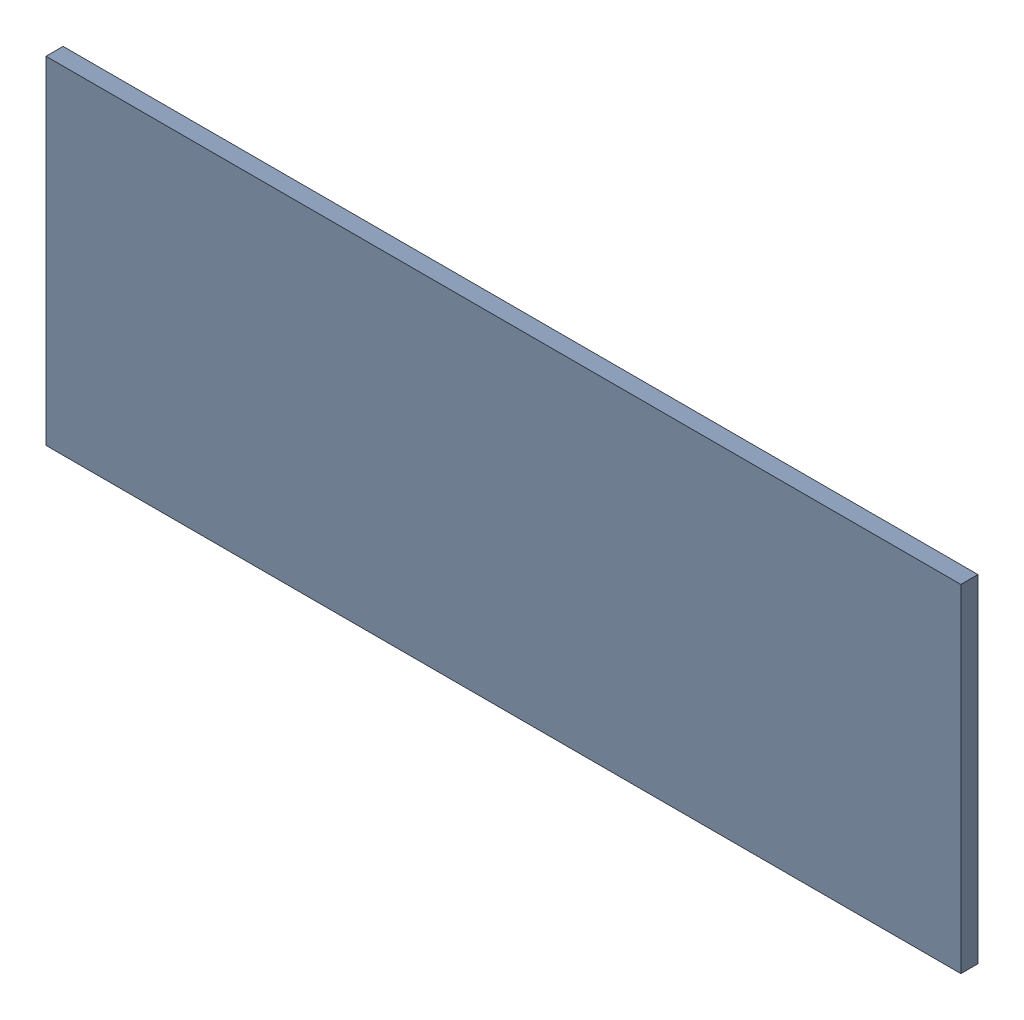
SolidWorks assembly Pad RAK4600-7(14.5mm,20mm) on Top Layer, configuration Predeterminado. Lengths in mm.
Overall size (1.9 0.7 0.04).
2 component instances, 1 part files, 0 mates.
Components (placement in the parent):
- Pad RAK4600-7(14.5mm,20mm) on Top Layer-1-1: Pad RAK4600-7(14.5mm,20mm) on Top Layer-1 [Predeterminado] at (-68.317 -44.187 -0.0457) size (1.9 0.7 0.04)
  - Pad RAK4600-7(14.5mm,20mm) on Top Layer-Part-1-1: Pad RAK4600-7(14.5mm,20mm) on Top Layer-Part-1 [Predeterminado] at origin size (1.9 0.7 0.04)
